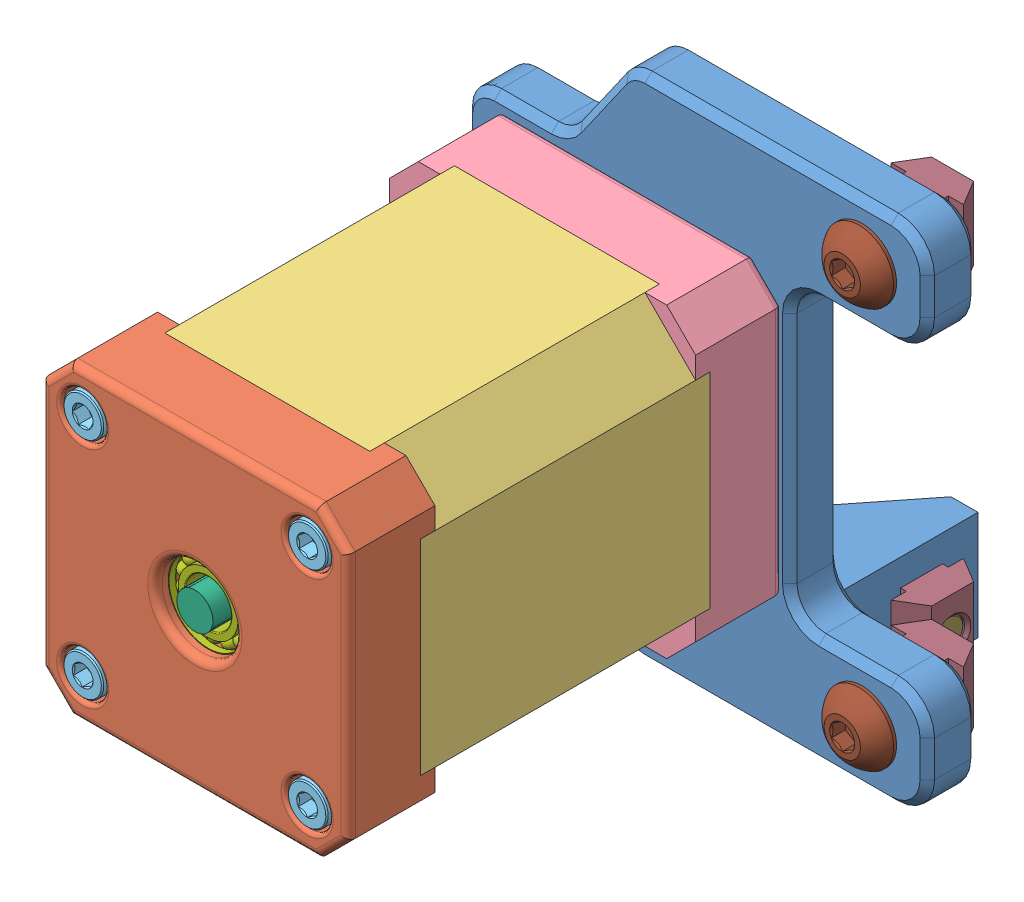
SolidWorks assembly Z_Stepper_Module, configuration Default. Lengths in mm.
Overall size (63.8 70.3 86.14).
27 component instances, 13 part files, 35 mates.
Components (placement in the parent):
- Z_Stepper_Mount_V2-1: Z_Stepper_Mount_V2 [Default] at origin size (63.8 70.3 26)
- NEMA_17_60mm_1.5A-1: NEMA_17_60mm_1.5A [Predeterminado] at (-10.3955 -4.6172 67) x (-1 0 0) z (0 0 -1) size (42.3 42.3 84.16)
  - Base-1: Base [Predeterminado] at (-10.3955 4.6172 0) size (42.3 42.3 12)
  - Body_60mm-1: Body_60mm [Predeterminado] at (-10.3955 4.6172 10) size (42.3 42.3 40)
  - FaceCap-1: FaceCap [Predeterminado] at (-10.3955 4.6172 60) x (-1 0 0) z (0 0 -1) size (42.3 42.3 14)
  - 3mmX50mm_Sockethead(McMaster_91290A137)-1: 3mmX50mm_Sockethead(McMaster_91290A137) [91290A137] at (5.1045 20.1172 53) x (-0.078076 -0.996947 0) z (0 0 1) size (5.5 5.5 53.26)
  - 3mmX50mm_Sockethead(McMaster_91290A137)-2: 3mmX50mm_Sockethead(McMaster_91290A137) [91290A137] at (-25.8955 20.1172 53) x (0.373638 -0.927575 0) z (0 0 1) size (5.5 5.5 53.26)
  - 3mmX50mm_Sockethead(McMaster_91290A137)-3: 3mmX50mm_Sockethead(McMaster_91290A137) [91290A137] at (-25.8955 -10.8828 53) x (-0.535522 -0.844521 0) z (0 0 1) size (5.5 5.5 53.26)
  - 3mmX50mm_Sockethead(McMaster_91290A137)-4: 3mmX50mm_Sockethead(McMaster_91290A137) [91290A137] at (5.1045 -10.8828 53) x (-0.438078 -0.898937 0) z (0 0 1) size (5.5 5.5 53.26)
  - Shaft_60mm-1: Shaft_60mm [Predeterminado] at (-10.3955 4.6172 0) x (0.574856 0.818255 0) z (0 0 1) size (5 5 84.02)
  - instrument ball bearing_68_am-2: instrument ball bearing_68_am [PreviewCfg] at (-10.3955 4.6172 56.5875) x (0 0 -1) z (0.994238 0.107199 0) size (3.17 12.7 12.7)
  - instrument ball bearing_68_am-4: instrument ball bearing_68_am [PreviewCfg] at (-10.3955 4.6172 3.4125) x (0 0 1) z (-0.739703 -0.672934 0) size (3.17 12.7 12.7)
- GT2_Aluminum_Timing_Pulley_20_Tooth-1: GT2_Aluminum_Timing_Pulley_20_Tooth [Default] at (0 0 1.0111) x (0.929025 -0.370016 0) z (0.370016 0.929025 0) size (15 14 15)
- 3mmX12mm_Buttonhead(McMaster_92095A183)-1: 3mmX12mm_Buttonhead(McMaster_92095A183) [92095A183] at (15.5 -15.5 -2.1) x (-0.99469 0.102916 0) z (0 0 -1) size (5.7 5.7 13.97)
- 3mmX12mm_Buttonhead(McMaster_92095A183)-2: 3mmX12mm_Buttonhead(McMaster_92095A183) [92095A183] at (15.5 15.5 -2.1) x (0.532454 0.846459 0) z (0 0 -1) size (5.7 5.7 13.97)
- 3mmX12mm_Buttonhead(McMaster_92095A183)-3: 3mmX12mm_Buttonhead(McMaster_92095A183) [92095A183] at (-15.5 15.5 -2.1) x (0.546373 0.837542 0) z (0 0 -1) size (5.7 5.7 13.97)
- 3mmX12mm_Buttonhead(McMaster_92095A183)-4: 3mmX12mm_Buttonhead(McMaster_92095A183) [92095A183] at (-15.5 -15.5 -2.1) x (-0.969488 0.245137 0) z (0 0 -1) size (5.7 5.7 13.97)
- M3_Flat_Washer(McMaster_93475A210)-1: M3_Flat_Washer(McMaster_93475A210) [93475A210] at (15.5 -15.5 0) size (7 7 0.45)
- M3_Flat_Washer(McMaster_93475A210)-2: M3_Flat_Washer(McMaster_93475A210) [93475A210] at (-15.5 15.5 0) size (7 7 0.45)
- M3_Flat_Washer(McMaster_93475A210)-3: M3_Flat_Washer(McMaster_93475A210) [93475A210] at (15.5 15.5 0) size (7 7 0.45)
- M3_Flat_Washer(McMaster_93475A210)-4: M3_Flat_Washer(McMaster_93475A210) [93475A210] at (-15.5 -15.5 0) size (7 7 0.45)
- 5mmX12mm_Buttonhead(McMaster_92095A210)-1: 5mmX12mm_Buttonhead(McMaster_92095A210) [92095A210] at (32.15 27.65 9.75) x (-1 0 0) z (0 0 1) size (9.5 9.5 15.22)
- 5mmX12mm_Buttonhead(McMaster_92095A210)-2: 5mmX12mm_Buttonhead(McMaster_92095A210) [92095A210] at (32.15 -27.65 9.75) x (-1 0 0) z (0 0 1) size (9.5 9.5 15.22)
- 5mmX10mm_Buttonhead(McMaster_91239A224)-1: 5mmX10mm_Buttonhead(McMaster_91239A224) [91239A224] at (14.4 -27.65 -10) x (0 0 1) z (-1 0 0) size (9.5 9.5 13.21)
- HNTTSN5-5-1: HNTTSN5-5 [Default] at (23.35 -27.65 -10) x (-1 0 0) z (0 -1 0) size (4.3 10 10)
- HNTTSN5-5-2: HNTTSN5-5 [Default] at (32.15 -27.65 -1.2) x (0 0 1) z (0 1 0) size (4.3 10 10)
- HNTTSN5-5-3: HNTTSN5-5 [Default] at (32.15 27.65 -1.2) x (0 0 1) z (0 -1 0) size (4.3 10 10)
Mates (geometry in assembly coordinates):
- Coincident1: coincident anti-aligned: plane of Z_Stepper_Mount_V2-1 through (36.15 30.15 7) normal (0 0 1); plane of NEMA_17_60mm_1.5A-1/FaceCap-1 through (0 0 7) normal (0 0 -1)
- Concentric1: concentric anti-aligned: cylinder of Z_Stepper_Mount_V2-1 through (0 0 7) axis (0 0 -1) radius 11.4; cylinder of NEMA_17_60mm_1.5A-1/FaceCap-1 through (0 0 5) axis (0 0 1) radius 11
- Parallel1: parallel aligned: plane of Z_Stepper_Mount_V2-1 through (-22.65 -18.65 7) normal (-1 0 0); plane of NEMA_17_60mm_1.5A-1/FaceCap-1 through (-21.15 17.15 19) normal (-1 0 0)
- Concentric2: concentric aligned: cylinder of NEMA_17_60mm_1.5A-1/Shaft_60mm-1 through (0 0 -17) axis (0 0 1) radius 2.5; cylinder of GT2_Aluminum_Timing_Pulley_20_Tooth-1 through (0 0 -12.9889) axis (0 0 1) radius 2.5
- Concentric4: concentric aligned: cylinder of Z_Stepper_Mount_V2-1 through (15.5 15.5 7) axis (0 0 -1) radius 1.65; cylinder of 3mmX12mm_Buttonhead(McMaster_92095A183)-2 through (15.5 15.5 -2.1) axis (0 0 -1) radius 2.85
- Concentric5: concentric aligned: cylinder of Z_Stepper_Mount_V2-1 through (15.5 -15.5 7) axis (0 0 -1) radius 1.65; cylinder of 3mmX12mm_Buttonhead(McMaster_92095A183)-1 through (15.5 -15.5 -2.1) axis (0 0 -1) radius 2.85
- Concentric6: concentric aligned: cylinder of Z_Stepper_Mount_V2-1 through (-15.5 -15.5 7) axis (0 0 -1) radius 1.65; cylinder of 3mmX12mm_Buttonhead(McMaster_92095A183)-4 through (-15.5 -15.5 -2.1) axis (0 0 -1) radius 2.85
- Concentric7: concentric aligned: cylinder of Z_Stepper_Mount_V2-1 through (-15.5 15.5 7) axis (0 0 -1) radius 1.65; cylinder of 3mmX12mm_Buttonhead(McMaster_92095A183)-3 through (-15.5 15.5 -2.1) axis (0 0 -1) radius 2.85
- Concentric8: concentric anti-aligned: cylinder of Z_Stepper_Mount_V2-1 through (15.5 15.5 7) axis (0 0 -1) radius 1.65; cylinder of M3_Flat_Washer(McMaster_93475A210)-3 through (15.5 15.5 -0.45) axis (0 0 1) radius 1.6
- Concentric9: concentric anti-aligned: cylinder of Z_Stepper_Mount_V2-1 through (-15.5 15.5 7) axis (0 0 -1) radius 1.65; cylinder of M3_Flat_Washer(McMaster_93475A210)-2 through (-15.5 15.5 -0.45) axis (0 0 1) radius 1.6
- Concentric10: concentric anti-aligned: cylinder of Z_Stepper_Mount_V2-1 through (-15.5 -15.5 7) axis (0 0 -1) radius 1.65; cylinder of M3_Flat_Washer(McMaster_93475A210)-4 through (-15.5 -15.5 -0.45) axis (0 0 1) radius 1.6
- Concentric11: concentric anti-aligned: cylinder of Z_Stepper_Mount_V2-1 through (15.5 -15.5 7) axis (0 0 -1) radius 1.65; cylinder of M3_Flat_Washer(McMaster_93475A210)-1 through (15.5 -15.5 -0.45) axis (0 0 1) radius 1.6
- Coincident5: coincident anti-aligned: plane of Z_Stepper_Mount_V2-1 through (36.15 30.15 0) normal (0 0 -1); plane of M3_Flat_Washer(McMaster_93475A210)-3 through (15.5 15.5 0) normal (0 0 1)
- Coincident6: coincident anti-aligned: plane of Z_Stepper_Mount_V2-1 through (36.15 30.15 0) normal (0 0 -1); plane of M3_Flat_Washer(McMaster_93475A210)-2 through (-15.5 15.5 0) normal (0 0 1)
- Coincident7: coincident anti-aligned: plane of Z_Stepper_Mount_V2-1 through (36.15 30.15 0) normal (0 0 -1); plane of M3_Flat_Washer(McMaster_93475A210)-4 through (-15.5 -15.5 0) normal (0 0 1)
- Coincident8: coincident anti-aligned: plane of Z_Stepper_Mount_V2-1 through (36.15 30.15 0) normal (0 0 -1); plane of M3_Flat_Washer(McMaster_93475A210)-1 through (15.5 -15.5 0) normal (0 0 1)
- Coincident11: coincident anti-aligned: plane of 3mmX12mm_Buttonhead(McMaster_92095A183)-2 through (13.0876 17.0175 -0.45) normal (0 0 1); plane of M3_Flat_Washer(McMaster_93475A210)-3 through (15.5 15.5 -0.45) normal (0 0 -1)
- Coincident12: coincident anti-aligned: plane of 3mmX12mm_Buttonhead(McMaster_92095A183)-3 through (-17.887 17.0572 -0.45) normal (0 0 1); plane of M3_Flat_Washer(McMaster_93475A210)-2 through (-15.5 15.5 -0.45) normal (0 0 -1)
- Coincident13: coincident anti-aligned: plane of 3mmX12mm_Buttonhead(McMaster_92095A183)-4 through (-16.1986 -18.263 -0.45) normal (0 0 1); plane of M3_Flat_Washer(McMaster_93475A210)-4 through (-15.5 -15.5 -0.45) normal (0 0 -1)
- Coincident14: coincident anti-aligned: plane of 3mmX12mm_Buttonhead(McMaster_92095A183)-1 through (15.2067 -18.3349 -0.45) normal (0 0 1); plane of M3_Flat_Washer(McMaster_93475A210)-1 through (15.5 -15.5 -0.45) normal (0 0 -1)
- Concentric12: concentric anti-aligned: cylinder of Z_Stepper_Mount_V2-1 through (32.15 27.65 7) axis (0 0 -1) radius 2.65; cylinder of 5mmX12mm_Buttonhead(McMaster_92095A210)-1 through (32.15 27.65 9.75) axis (0 0 1) radius 4.75
- Concentric13: concentric anti-aligned: cylinder of Z_Stepper_Mount_V2-1 through (32.15 -27.65 7) axis (0 0 -1) radius 2.65; cylinder of 5mmX12mm_Buttonhead(McMaster_92095A210)-2 through (32.15 -27.65 9.75) axis (0 0 1) radius 4.75
- Coincident15: coincident anti-aligned: plane of Z_Stepper_Mount_V2-1 through (36.15 30.15 7) normal (0 0 1); plane of 5mmX12mm_Buttonhead(McMaster_92095A210)-2 through (32.15 -22.9 7) normal (0 0 -1)
- Coincident16: coincident anti-aligned: plane of Z_Stepper_Mount_V2-1 through (36.15 30.15 7) normal (0 0 1); plane of 5mmX12mm_Buttonhead(McMaster_92095A210)-1 through (32.15 32.4 7) normal (0 0 -1)
- Concentric14: concentric anti-aligned: cylinder of Z_Stepper_Mount_V2-1 through (17.15 -27.65 -10) axis (1 0 0) radius 2.65; cylinder of 5mmX10mm_Buttonhead(McMaster_91239A224)-1 through (14.4 -27.65 -10) axis (-1 0 0) radius 4.75
- Coincident17: coincident anti-aligned: plane of Z_Stepper_Mount_V2-1 through (17.15 -27.65 -10) normal (-1 0 0); plane of 5mmX10mm_Buttonhead(McMaster_91239A224)-1 through (17.15 -32.4 -10) normal (1 0 0)
- Concentric15: concentric aligned: cylinder of Z_Stepper_Mount_V2-1 through (17.15 -27.65 -10) axis (1 0 0) radius 2.65; cylinder of HNTTSN5-5-1 through (23.35 -27.65 -10) axis (1 0 0) radius 2.067
- Parallel2: parallel aligned: plane of Z_Stepper_Mount_V2-1 through (2.15 -35.15 7) normal (0 -1 0); plane of HNTTSN5-5-1 through (23.35 -32.65 -10) normal (0 -1 0)
- Distance1: distance = 2 mm anti-aligned: plane of Z_Stepper_Mount_V2-1 through (22.15 -20.15 0) normal (1 0 0); plane of HNTTSN5-5-1 through (24.15 -32.65 -12.9) normal (-1 0 0)
- Concentric16: concentric aligned: cylinder of Z_Stepper_Mount_V2-1 through (32.15 -27.65 7) axis (0 0 -1) radius 2.65; cylinder of HNTTSN5-5-2 through (32.15 -27.65 -1.2) axis (0 0 -1) radius 2.067
- Parallel3: parallel aligned: plane of Z_Stepper_Mount_V2-1 through (2.15 -35.15 7) normal (0 -1 0); plane of HNTTSN5-5-2 through (32.15 -32.65 -1.2) normal (0 -1 0)
- Concentric17: concentric aligned: cylinder of Z_Stepper_Mount_V2-1 through (32.15 27.65 7) axis (0 0 -1) radius 2.65; cylinder of HNTTSN5-5-3 through (32.15 27.65 -1.2) axis (0 0 -1) radius 2.067
- Parallel4: parallel aligned: plane of Z_Stepper_Mount_V2-1 through (2.15 -35.15 7) normal (0 -1 0); plane of HNTTSN5-5-3 through (32.15 22.65 -1.2) normal (0 -1 0)
- Distance4: distance = 2 mm anti-aligned: plane of Z_Stepper_Mount_V2-1 through (36.15 30.15 0) normal (0 0 -1); plane of HNTTSN5-5-3 through (37.15 22.65 -2) normal (0 0 1)
- Distance5: distance = 2 mm anti-aligned: plane of HNTTSN5-5-2 through (35.05 -22.65 -2) normal (0 0 1); plane of Z_Stepper_Mount_V2-1 through (36.15 30.15 0) normal (0 0 -1)
